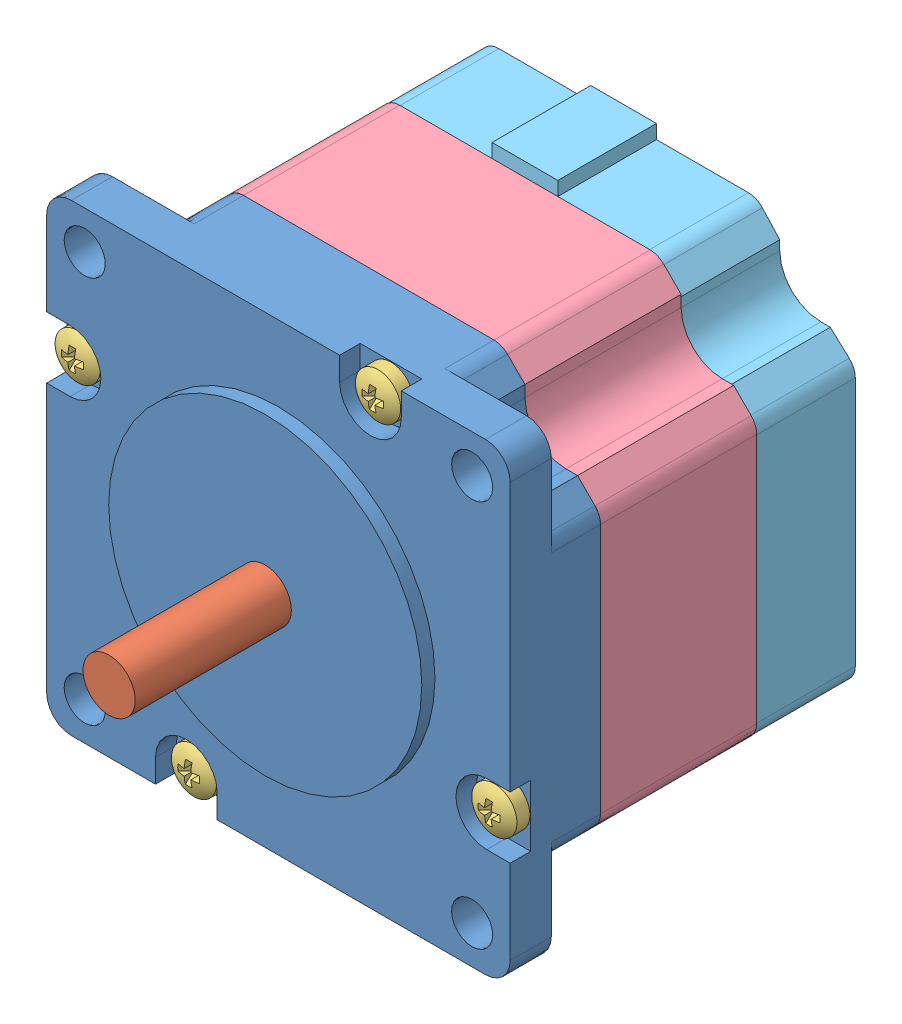
SolidWorks assembly ST5918X1008, configuration Standard. Lengths in mm.
Overall size (56.4 58.22 62.6).
9 component instances, 5 part files, 0 mates.
Components (placement in the parent):
- Frontcap_ST5918_1-1: Frontcap_ST5918_1 [Standard] at (0 0 -6.3) size (56.4 56.4 12.6)
- shaft_forward_5709_1-1: shaft_forward_5709_1 [Standard] at (0 0 25.3) x (0.985699 0.168514 0) z (0 0 -1) size (6.35 6.35 19)
- Schrauben_ISO_7045_M3_1-1: Schrauben_ISO_7045_M3_1 [Standard] at (-11.2 -25.35 2.2) x (1 0 0) z (0 -1 0) size (5.57 2.46 5.76)
- Schrauben_ISO_7045_M3_1-2: Schrauben_ISO_7045_M3_1 [Standard] at (25.35 -11.2 2.2) x (1 0 0) z (0 -1 0) size (5.57 2.46 5.76)
- Schrauben_ISO_7045_M3_1-3: Schrauben_ISO_7045_M3_1 [Standard] at (11.2 25.35 2.2) x (1 0 0) z (0 -1 0) size (5.57 2.46 5.76)
- Schrauben_ISO_7045_M3_1-4: Schrauben_ISO_7045_M3_1 [Standard] at (-25.35 11.2 2.2) x (1 0 0) z (0 -1 0) size (5.57 2.46 5.76)
- Stator_5918_X-1: Stator_5918_X [Standard] at (0 0 -6.3) x (1 0 0) z (0 0 -1) size (56.4 56.4 19)
- Endcap ST5918_kompl_1-1: Endcap ST5918_kompl_1 [Standard] at (0 0.85 -31.3) x (1 0 0) z (0 0 -1) size (56.4 58.1 12)
  - Endcap_5918_1-1: Endcap_5918_1 [Standard] at (0 0.85 -6) size (56.4 58.1 12)
